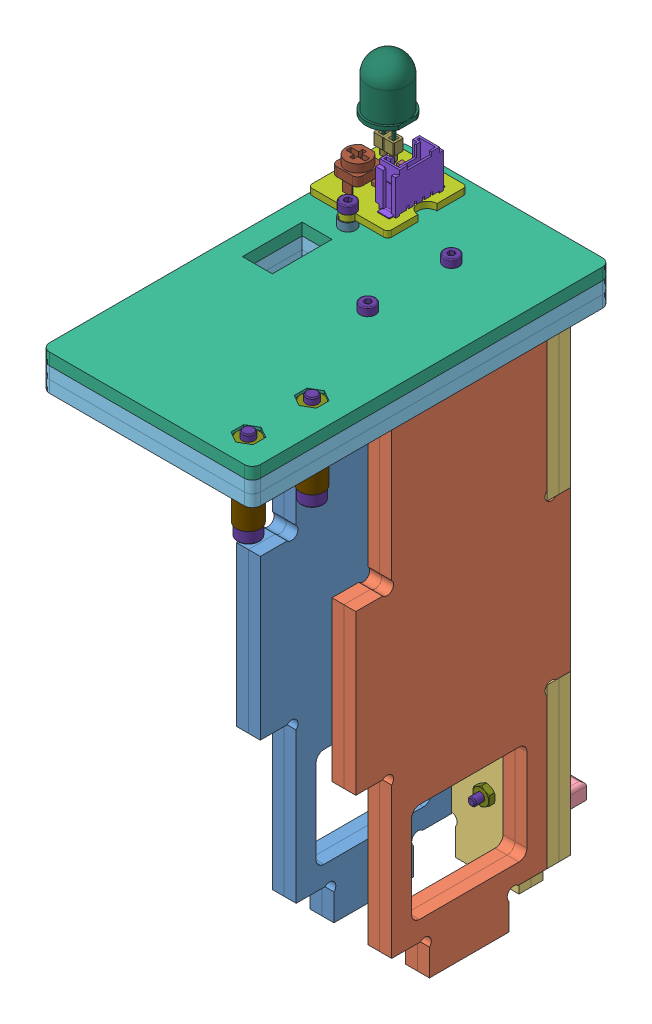
SolidWorks assembly pilier_droit, configuration Défaut. Lengths in mm.
Overall size (53 165.17 99).
42 component instances, 19 part files, 81 mates.
Components (placement in the parent):
- pilier-cote-2-1: pilier-cote-2 [Défaut] at (-45.8322 -68.3923 0) size (3 133 54)
- pilier-cote-3-2: pilier-cote-3 [Défaut] at (-18.8322 -68.3923 0) size (3 133 54)
- pilier-devant-1: pilier-devant [Défaut] at (-45.8322 -68.3923 -54) size (30 133 3)
- pilier-devant-2: pilier-devant [Défaut] at (-45.8322 -68.3923 -51) size (30 133 3)
- pilier-cote-2-3: pilier-cote-2 [Défaut] at (-42.8322 -68.3923 0) size (3 133 54)
- pilier-cote-3-4: pilier-cote-3 [Défaut] at (-21.8322 -68.3923 0) size (3 133 54)
- equerre-1: equerre [Défaut] at (-30.8322 -59.3923 -54) x (-1 0 0) z (0 0 -1) size (10 14 14)
- pilier_droit-chapeau-1-1: pilier_droit-chapeau-1 [Défaut] at (-63.8322 60.6077 31) size (53 3 90)
- pilier_droit-chapeau-1-2: pilier_droit-chapeau-1 [Défaut] at (-63.8322 63.6077 31) size (53 3 90)
- pilier_droit-chapeau-2-1: pilier_droit-chapeau-2 [Défaut] at (-63.8322 66.6077 31) size (53 3 90)
- Grove support LED-1: Grove support LED [Défaut] at (-59.2877 75.7919 -44) size (20 13.2 23.6)
  - PCB grove 20x20-1: PCB grove 20x20 [Défaut] at (7.4555 -4.1841 0) size (20 1.6 23.6)
  - Connecteur Grove (droit CMS)-1: Connecteur Grove (droit CMS) [Défaut] at (10.4555 -2.5841 0) x (-1 0 0) z (0 1 0) size (6.5 14 10)
  - 603 resistor 102-2: 603 resistor 102 [Default] at (3.6365 -2.5841 -1.49) size (2.36 0.62 1.03)
  - 603 cap on pad-1: 603 cap on pad [Défaut] at (8.4655 -2.5841 -6.62) x (0 0 1) z (-1 0 0) size (2.76 0.91 1.12)
  - 603 resistor 102-3: 603 resistor 102 [Default] at (6.6365 -2.5841 -1.49) size (2.36 0.62 1.03)
  - 603 resistor 102-4: 603 resistor 102 [Default] at (6.6365 -2.5841 -2.99) size (2.36 0.62 1.03)
  - Pot - RES_VAR1-1: Pot - RES_VAR1 [Défaut] at (4.0824 2.7159 4.0972) size (6.5 10.5 7.06)
  - Contact F-1: Contact F [Défaut] at (0.621 0.0871 -5.7728) size (2.54 7.5 2.54)
  - ssot3-1: ssot3 [Default] at (6.0932 -2.5841 -5.7439) size (3 1.13 3.09)
  - Contact F-2: Contact F [Défaut] at (3.161 0.0871 -5.7728) size (2.54 7.5 2.54)
- entretoise-grove-1: entretoise-grove [Défaut] at (-51.8322 71.6077 -34) x (1 0 0) z (0 -1 0) size (4 4 2)
- chapeau_pilier_droit-led_jaune-10-1: chapeau_pilier_droit-led_jaune-10 [Default] at (-57.5966 83.2789 -49.8228) x (1 0 0) z (0 1 0) size (10.5 11 23.5)
- entretoise-grove-2: entretoise-grove [Défaut] at (-51.8322 71.6077 -54) x (1 0 0) z (0 -1 0) size (4 4 2)
- ecrou-h-1: ecrou-h [6007 HU M2] at (-51.8322 60.6077 -54) x (0.5 0 0.866025) z (-0.866025 0 0.5) size (4 1.6 4.62)
- vis-chc-1: vis-chc [Vis CHC M2x16] at (-51.8322 73.2077 -54) x (0.657231 0 0.753689) z (-0.753689 0 0.657231) size (3.8 18 3.8)
- vis-chc-2: vis-chc [Vis CHC M2x16] at (-51.8322 73.2077 -34) x (0.657231 0 0.753689) z (-0.753689 0 0.657231) size (3.8 18 3.8)
- ecrou-h-2: ecrou-h [6007 HU M2] at (-51.8322 60.6077 -34) x (-0.866025 0 0.5) z (-0.5 0 -0.866025) size (4 1.6 4.62)
- vis-chc-3: vis-chc [Vis CHC M3x20] at (-18.8322 50.6077 24) x (-0.990761 0 0.135623) z (0.135623 0 0.990761) size (5.5 23 5.5)
- vis-chc-4: vis-chc [Vis CHC M3x20] at (-18.8322 50.6077 8) x (-0.990761 0 0.135623) z (0.135623 0 0.990761) size (5.5 23 5.5)
- ecrou-h-4: ecrou-h [6012 HU M3] at (-18.8322 69.0077 8) x (0.5 0 0.866025) z (-0.866025 0 0.5) size (5.5 2.4 6.35)
- ecrou-h-5: ecrou-h [6012 HU M3] at (-18.8322 69.0077 24) x (-0.5 0 0.866025) z (-0.866025 0 -0.5) size (5.5 2.4 6.35)
- ecrou-h-6: ecrou-h [6007 HU M2] at (-30.8322 51.6077 -46) x (-0.866025 0.5 0) z (-0.5 -0.866025 0) size (4 1.6 4.62)
- ecrou-h-7: ecrou-h [6007 HU M2] at (-30.8322 58.6077 -39) x (0 0 -1) z (1 0 0) size (4 1.6 4.62)
- vis-chc-5: vis-chc [Vis CHC M2x12] at (-30.8322 51.6077 -54) x (0.657231 0.753689 0) z (-0.753689 0.657231 0) size (3.8 14 3.8)
- vis-chc-6: vis-chc [Vis CHC M2x16] at (-30.8322 69.6077 -39) x (-0.137988 0 -0.990434) z (0.990434 0 -0.137988) size (3.8 18 3.8)
- vis-chc-7: vis-chc [Vis CHC M2x16] at (-30.8322 69.6077 -18) x (-0.137988 0 -0.990434) z (0.990434 0 -0.137988) size (3.8 18 3.8)
- grille-patin-1: grille-patin [Défaut] at (-18.8322 60.6077 8) x (0.804119 0 0.594469) z (0 -1 0) size (6 6 10)
- grille-patin-2: grille-patin [Défaut] at (-18.8322 60.6077 24) x (-0.010244 0 0.999948) z (0 -1 0) size (6 6 10)
- equerre-double_ecrou-2: equerre-double_ecrou [Défaut] at (-30.8322 60.6077 -48) x (-1 0 0) z (0 0 1) size (10 14 14)
- vis-chc-8: vis-chc [Vis CHC M2x12] at (-30.8322 -50.3923 -56) x (0.657231 0.753689 0) z (-0.753689 0.657231 0) size (3.8 14 3.8)
- ecrou-h-8: ecrou-h [6007 HU M2] at (-30.8322 -50.3923 -46.4) x (0.5 -0.866025 0) z (-0.866025 -0.5 0) size (4 1.6 4.62)
Mates (geometry in assembly coordinates):
- Coïncidente1: coincident aligned: plane of pilier-cote-2-1 through (-42.8322 60.6077 -40.7627) normal (0 1 0); plane of pilier-devant-1 through (-41.0949 60.6077 -51) normal (0 1 0)
- Coïncidente2: coincident aligned: plane of pilier-cote-2 through (-15.8322 60.6077 -40.7627) normal (0 1 0); plane of pilier-devant-1 through (-20.5694 60.6077 -51) normal (0 1 0)
- Coïncidente3: coincident aligned: plane of pilier-cote-2-1 through (-45.8322 -20.5236 -49.1314) normal (-1 0 0); plane of pilier-devant-1 through (-45.8322 20.6077 -51) normal (-1 0 0)
- Coïncidente4: coincident aligned: plane of pilier-cote-2-1 through (-42.8322 20.6077 -54) normal (0 0 -1); plane of pilier-devant-1 through (-21.7008 -60.5236 -54) normal (0 0 -1)
- Coïncidente5: coincident aligned: plane of pilier-cote-2 through (-15.8322 20.6077 -54) normal (0 0 -1); plane of pilier-devant-1 through (-21.7008 -60.5236 -54) normal (0 0 -1)
- Coïncidente6: coincident aligned: plane of pilier-cote-2 through (-15.8322 -20.5236 -49.1314) normal (1 0 0); plane of pilier-devant-1 through (-15.8322 20.6077 -51) normal (1 0 0)
- Coïncidente7: coincident anti-aligned: plane of pilier-devant-1 through (-21.7008 -60.5236 -51) normal (0 0 1); plane of pilier-devant-2 through (-21.7008 -60.5236 -51) normal (0 0 -1)
- Coïncidente8: coincident aligned: plane of pilier-devant-1 through (-38.8322 64.6077 -51) normal (0 1 0); plane of pilier-devant-2 through (-38.8322 64.6077 -48) normal (0 1 0)
- Coïncidente9: coincident aligned: plane of pilier-devant-1 through (-15.8322 20.6077 -51) normal (1 0 0); plane of pilier-devant-2 through (-15.8322 20.6077 -48) normal (1 0 0)
- Coïncidente11: coincident anti-aligned: plane of pilier-cote-2-1 through (-42.8322 -20.5236 -49.1314) normal (1 0 0); plane of pilier-cote-2-3 through (-42.8322 -20.5236 -49.1314) normal (-1 0 0)
- Coïncidente12: coincident aligned: plane of pilier-cote-2-1 through (-42.8322 64.6077 -18.5) normal (0 1 0); plane of pilier-cote-2-3 through (-39.8322 64.6077 -18.5) normal (0 1 0)
- Coïncidente13: coincident aligned: plane of pilier-cote-2-1 through (-42.8322 20.6077 -54) normal (0 0 -1); plane of pilier-cote-2-3 through (-39.8322 20.6077 -54) normal (0 0 -1)
- Coïncidente14: coincident anti-aligned: plane of pilier-cote-2 through (-18.8322 -20.5236 -49.1314) normal (-1 0 0); plane of pilier-cote-4 through (-18.8322 -20.5236 -49.1314) normal (1 0 0)
- Coïncidente15: coincident aligned: plane of pilier-cote-2 through (-15.8322 64.6077 -18.5) normal (0 1 0); plane of pilier-cote-4 through (-18.8322 64.6077 -18.5) normal (0 1 0)
- Coïncidente16: coincident: line of pilier-cote-2 through (-18.8322 22.8705 -48) axis (0 1 0); plane of pilier-cote-4 through (-18.8322 60.6077 -48) normal (0 0 -1)
- Coïncidente17: coincident anti-aligned: plane of pilier-devant-1 through (-21.7008 -60.5236 -54) normal (0 0 -1); plane of equerre-1 through (-30.8322 -59.3923 -54) normal (0 0 1)
- Coïncidente18: coincident aligned: plane of pilier-devant-1 through (-20.5694 -59.3923 -51) normal (0 -1 0); plane of equerre-1 through (-25.8322 -59.3923 -58) normal (0 -1 0)
- Coaxiale1: concentric anti-aligned: cylinder of pilier-devant-1 through (-30.8322 -50.3923 -54) axis (0 0 1) radius 1; cylinder of equerre-1 through (-30.8322 -50.3923 -54) axis (0 0 -1) radius 1
- Coïncidente19: coincident anti-aligned: plane of pilier-devant-2 through (-21.7008 -60.5236 -48) normal (0 0 1); plane of chapeau_pilier_droit-1 through (-25.0949 63.6077 -48) normal (0 0 -1)
- Coïncidente20: coincident anti-aligned: plane of pilier-devant-1 through (-38.8322 62.8705 -51) normal (-1 0 0); plane of chapeau_pilier_droit-1 through (-38.8322 63.6077 -51.7373) normal (1 0 0)
- Coïncidente21: coincident anti-aligned: plane of pilier-devant-1 through (-41.0949 60.6077 -51) normal (0 1 0); plane of chapeau_pilier_droit-1 through (-12.8322 60.6077 -57) normal (0 -1 0)
- Coïncidente22: coincident anti-aligned: plane of chapeau_pilier_droit-1 through (-12.8322 63.6077 -57) normal (0 1 0); plane of chapeau_pilier_droit-2 through (-12.8322 63.6077 -57) normal (0 -1 0)
- Coïncidente23: coincident aligned: plane of chapeau_pilier_droit-1 through (-63.8322 63.6077 -57) normal (-1 0 0); plane of chapeau_pilier_droit-2 through (-63.8322 66.6077 -57) normal (-1 0 0)
- Coïncidente24: coincident aligned: plane of chapeau_pilier_droit-1 through (-61.8322 63.6077 -59) normal (0 0 -1); plane of chapeau_pilier_droit-2 through (-61.8322 66.6077 -59) normal (0 0 -1)
- Coïncidente25: coincident anti-aligned: plane of chapeau_pilier_droit-2 through (-12.8322 66.6077 -57) normal (0 1 0); plane of pilier_droit-chapeau-2-1 through (-12.8322 66.6077 -57) normal (0 -1 0)
- Coïncidente26: coincident aligned: plane of chapeau_pilier_droit-2 through (-63.8322 66.6077 -57) normal (-1 0 0); plane of pilier_droit-chapeau-2-1 through (-63.8322 69.6077 -57) normal (-1 0 0)
- Coïncidente27: coincident aligned: plane of chapeau_pilier_droit-2 through (-61.8322 66.6077 -59) normal (0 0 -1); plane of pilier_droit-chapeau-2-1 through (-61.8322 69.6077 -59) normal (0 0 -1)
- Coaxiale2: concentric anti-aligned: cylinder of Grove support LED-1/PCB grove 20x20-1 through (-51.8322 73.2077 -34) axis (0 -1 0) radius 1.1; cylinder of entretoise-grove-1 through (-51.8322 69.6077 -34) axis (0 1 0) radius 1
- Distance1: distance = 5 mm: line of Grove support LED-1/Contact F-2 through (-55.8266 78.2789 -50.0728) axis (-1 0 0); line of chapeau_pilier_droit-led_jaune-10-1 through (-56.3266 73.2789 -50.0728) axis (1 0 0)
- Coaxiale3: concentric anti-aligned: cylinder of Grove support LED-1/PCB grove 20x20-1 through (-51.8322 73.2077 -54) axis (0 -1 0) radius 1.1; cylinder of entretoise-grove-2 through (-51.8322 69.6077 -54) axis (0 1 0) radius 1
- Coïncidente28: coincident anti-aligned: plane of Grove support LED-1/PCB grove 20x20-1 through (-51.8322 71.6077 -44) normal (0 -1 0); plane of entretoise-grove-1 through (-51.8322 71.6077 -34) normal (0 1 0)
- Coïncidente29: coincident anti-aligned: plane of Grove support LED-1/Contact F-2 through (-55.8266 78.6789 -49.4728) normal (-1 0 0); plane of chapeau_pilier_droit-led_jaune-10-1 through (-55.8266 83.2789 -50.0728) normal (1 0 0)
- Coïncidente30: coincident anti-aligned: plane of Grove support LED-1/Contact F-2 through (-56.4266 78.6789 -50.0728) normal (0 0 1); plane of chapeau_pilier_droit-led_jaune-10-1 through (-57.5966 83.2789 -50.0728) normal (0 0 -1)
- Coïncidente31: coincident anti-aligned: plane of Grove support LED-1/PCB grove 20x20-1 through (-51.8322 71.6077 -44) normal (0 -1 0); plane of entretoise-grove-2 through (-51.8322 71.6077 -54) normal (0 1 0)
- Coïncidente32: coincident anti-aligned: plane of pilier_droit-chapeau-2-1 through (-12.8322 69.6077 -57) normal (0 1 0); plane of entretoise-grove-2 through (-51.8322 69.6077 -54) normal (0 -1 0)
- Coaxiale4: concentric aligned: cylinder of pilier_droit-chapeau-2-1 through (-51.8322 66.6077 -54) axis (0 1 0) radius 1; cylinder of entretoise-grove-2 through (-51.8322 69.6077 -54) axis (0 1 0) radius 1
- Coaxiale5: concentric anti-aligned: cylinder of pilier_droit-chapeau-2-1 through (-51.8322 66.6077 -34) axis (0 1 0) radius 1; cylinder of Grove support LED-1/PCB grove 20x20-1 through (-51.8322 73.2077 -34) axis (0 -1 0) radius 1.1
- Coaxiale6: concentric anti-aligned: cylinder of Grove support LED-1/PCB grove 20x20-1 through (-51.8322 73.2077 -34) axis (0 -1 0) radius 1.1; cylinder of vis-chc-2 through (-51.8322 57.2077 -34) axis (0 1 0) radius 1
- Coaxiale7: concentric anti-aligned: cylinder of Grove support LED-1/PCB grove 20x20-1 through (-51.8322 73.2077 -54) axis (0 -1 0) radius 1.1; cylinder of vis-chc-1 through (-51.8322 57.2077 -54) axis (0 1 0) radius 1
- Coïncidente33: coincident anti-aligned: plane of Grove support LED-1/PCB grove 20x20-1 through (-51.8322 73.2077 -44) normal (0 1 0); plane of vis-chc-2 through (-51.8322 73.2077 -34) normal (0 -1 0)
- Coïncidente34: coincident anti-aligned: plane of Grove support LED-1/PCB grove 20x20-1 through (-51.8322 73.2077 -44) normal (0 1 0); plane of vis-chc-1 through (-51.8322 73.2077 -54) normal (0 -1 0)
- Coïncidente35: coincident anti-aligned: plane of chapeau_pilier_droit-1 through (-12.8322 60.6077 -57) normal (0 -1 0); plane of ecrou-h-1 through (-49.8322 60.6077 -52.8453) normal (0 1 0)
- Coaxiale8: concentric aligned: cylinder of ecrou-h-1 through (-51.8322 59.0077 -54) axis (0 1 0) radius 0.7835; cylinder of vis-chc-1 through (-51.8322 57.2077 -54) axis (0 1 0) radius 1
- Parallèle1: parallel aligned: plane of chapeau_pilier_droit-1 through (-63.8322 63.6077 -57) normal (-1 0 0); plane of ecrou-h-1 through (-53.8322 59.0077 -55.1547) normal (-1 0 0)
- Coïncidente37: coincident anti-aligned: plane of chapeau_pilier_droit-1 through (-12.8322 60.6077 -57) normal (0 -1 0); plane of ecrou-h-2 through (-52.9869 60.6077 -32) normal (0 1 0)
- Coaxiale9: concentric aligned: cylinder of vis-chc-2 through (-51.8322 57.2077 -34) axis (0 1 0) radius 1; cylinder of ecrou-h-2 through (-51.8322 59.0077 -34) axis (0 1 0) radius 0.7835
- Parallèle2: parallel aligned: plane of chapeau_pilier_droit-1 through (-61.8322 63.6077 -59) normal (0 0 -1); plane of ecrou-h-2 through (-50.6775 59.0077 -36) normal (0 0 -1)
- Coaxiale10: concentric anti-aligned: cylinder of chapeau_pilier_droit-1 through (-18.8322 63.6077 24) axis (0 -1 0) radius 1.5; cylinder of entretoise-6x10-2 through (-18.8322 50.6077 24) axis (0 1 0) radius 2
- Coaxiale11: concentric anti-aligned: cylinder of chapeau_pilier_droit-1 through (-18.8322 63.6077 8) axis (0 -1 0) radius 1.5; cylinder of entretoise-6x10-1 through (-18.8322 50.6077 8) axis (0 1 0) radius 2
- Coïncidente39: coincident anti-aligned: plane of chapeau_pilier_droit-1 through (-12.8322 60.6077 -57) normal (0 -1 0); plane of entretoise-6x10-2 through (-18.8322 60.6077 24) normal (0 1 0)
- Coïncidente40: coincident anti-aligned: plane of chapeau_pilier_droit-1 through (-12.8322 60.6077 -57) normal (0 -1 0); plane of entretoise-6x10-1 through (-18.8322 60.6077 8) normal (0 1 0)
- Coaxiale12: concentric anti-aligned: cylinder of entretoise-6x10-2 through (-18.8322 50.6077 24) axis (0 1 0) radius 2; cylinder of vis-chc-3 through (-18.8322 70.6077 24) axis (0 -1 0) radius 1.5
- Coïncidente41: coincident anti-aligned: plane of entretoise-6x10-2 through (-18.8322 50.6077 24) normal (0 -1 0); plane of vis-chc-3 through (-18.8322 50.6077 24) normal (0 1 0)
- Coaxiale13: concentric anti-aligned: cylinder of entretoise-6x10-1 through (-18.8322 50.6077 8) axis (0 1 0) radius 2; cylinder of vis-chc-4 through (-18.8322 70.6077 8) axis (0 -1 0) radius 1.5
- Coïncidente42: coincident anti-aligned: plane of entretoise-6x10-1 through (-18.8322 50.6077 8) normal (0 -1 0); plane of vis-chc-4 through (-18.8322 50.6077 8) normal (0 1 0)
- Coaxiale14: concentric anti-aligned: cylinder of vis-chc-4 through (-18.8322 70.6077 8) axis (0 -1 0) radius 1.5; cylinder of ecrou-h-4 through (-18.8322 66.6077 8) axis (0 1 0) radius 1.2295
- Parallèle3: parallel anti-aligned: plane of pilier_droit-chapeau-2-1 through (-21.6035 66.6077 6.4971) normal (1 0 0); plane of ecrou-h-4 through (-21.5822 66.6077 6.4123) normal (-1 0 0)
- Coaxiale15: concentric anti-aligned: cylinder of vis-chc-3 through (-18.8322 70.6077 24) axis (0 -1 0) radius 1.5; cylinder of ecrou-h-5 through (-18.8322 66.6077 24) axis (0 1 0) radius 1.2295
- Parallèle4: parallel anti-aligned: plane of pilier_droit-chapeau-2-1 through (-21.6035 66.6077 22.4) normal (1 0 0); plane of ecrou-h-5 through (-21.5822 66.6077 22.4123) normal (-1 0 0)
- Coïncidente45: coincident anti-aligned: plane of chapeau_pilier_droit-2 through (-12.8322 66.6077 -57) normal (0 1 0); plane of ecrou-h-5 through (-18.8322 66.6077 27.1754) normal (0 -1 0)
- Coïncidente46: coincident anti-aligned: plane of chapeau_pilier_droit-2 through (-12.8322 66.6077 -57) normal (0 1 0); plane of ecrou-h-4 through (-16.0822 66.6077 9.5877) normal (0 -1 0)
- Coaxiale16: concentric aligned: cylinder of pilier-devant-2 through (-30.8322 51.6077 -51) axis (0 0 1) radius 1; cylinder of equerre-double_ecrou-2 through (-30.8322 51.6077 -48) axis (0 0 1) radius 1
- Coïncidente47: coincident anti-aligned: plane of pilier-devant-2 through (-21.7008 -60.5236 -48) normal (0 0 1); plane of equerre-double_ecrou-2 through (-30.8322 60.6077 -48) normal (0 0 -1)
- Coïncidente48: coincident anti-aligned: plane of chapeau_pilier_droit-1 through (-12.8322 60.6077 -57) normal (0 -1 0); plane of equerre-double_ecrou-2 through (-25.8322 60.6077 -44) normal (0 1 0)
- Coaxiale17: concentric anti-aligned: cylinder of equerre-double_ecrou-2 through (-30.8322 51.6077 -48) axis (0 0 1) radius 1; cylinder of ecrou-h-6 through (-30.8322 51.6077 -44.4) axis (0 0 -1) radius 0.7835
- Parallèle5: parallel anti-aligned: plane of equerre-double_ecrou-2 through (-29.6672 49.5899 -46) normal (-0.866025 0.5 0); plane of ecrou-h-6 through (-28.5228 51.6077 -44.4) normal (0.866025 -0.5 0)
- Coïncidente51: coincident anti-aligned: plane of equerre-double_ecrou-2 through (-30.8322 60.6077 -46) normal (0 0 1); plane of ecrou-h-6 through (-31.9869 53.6077 -46) normal (0 0 -1)
- Coaxiale18: concentric anti-aligned: cylinder of equerre-double_ecrou-2 through (-30.8322 60.6077 -39) axis (0 -1 0) radius 1; cylinder of ecrou-h-7 through (-30.8322 57.0077 -39) axis (0 1 0) radius 0.7835
- Parallèle6: parallel anti-aligned: plane of equerre-double_ecrou-2 through (-31.9972 58.6077 -41.0178) normal (0 0 1); plane of ecrou-h-7 through (-29.6775 57.0077 -41) normal (0 0 -1)
- Coïncidente53: coincident anti-aligned: plane of equerre-double_ecrou-2 through (-30.8322 58.6077 -48) normal (0 -1 0); plane of ecrou-h-7 through (-31.9869 58.6077 -41) normal (0 1 0)
- Coaxiale19: concentric anti-aligned: cylinder of pilier-devant-1 through (-30.8322 51.6077 -54) axis (0 0 1) radius 1; cylinder of vis-chc-5 through (-30.8322 51.6077 -42) axis (0 0 -1) radius 1
- Coïncidente54: coincident anti-aligned: plane of pilier-devant-1 through (-21.7008 -60.5236 -54) normal (0 0 -1); plane of vis-chc-5 through (-30.8322 51.6077 -54) normal (0 0 1)
- Coaxiale20: concentric aligned: cylinder of pilier_droit-chapeau-2-1 through (-30.8322 66.6077 -39) axis (0 1 0) radius 1; cylinder of vis-chc-6 through (-30.8322 53.6077 -39) axis (0 1 0) radius 1
- Coïncidente55: coincident anti-aligned: plane of pilier_droit-chapeau-2-1 through (-12.8322 69.6077 -57) normal (0 1 0); plane of vis-chc-6 through (-30.8322 69.6077 -39) normal (0 -1 0)
- Coaxiale21: concentric aligned: cylinder of pilier_droit-chapeau-2-1 through (-30.8322 66.6077 -18) axis (0 1 0) radius 1; cylinder of vis-chc-7 through (-30.8322 53.6077 -18) axis (0 1 0) radius 1
- Coïncidente56: coincident anti-aligned: plane of pilier_droit-chapeau-2-1 through (-12.8322 69.6077 -57) normal (0 1 0); plane of vis-chc-7 through (-30.8322 69.6077 -18) normal (0 -1 0)
- Coaxiale22: concentric aligned: cylinder of equerre-1 through (-30.8322 -50.3923 -54) axis (0 0 -1) radius 1; cylinder of vis-chc-8 through (-30.8322 -50.3923 -44) axis (0 0 -1) radius 1
- Coïncidente57: coincident anti-aligned: plane of equerre-1 through (-30.8322 -50.3923 -56) normal (0 0 -1); plane of vis-chc-8 through (-30.8322 -50.3923 -56) normal (0 0 1)
- Coaxiale23: concentric anti-aligned: cylinder of vis-chc-8 through (-30.8322 -50.3923 -44) axis (0 0 -1) radius 1; cylinder of ecrou-h-8 through (-30.8322 -50.3923 -48) axis (0 0 1) radius 0.7835
- Coïncidente58: coincident anti-aligned: plane of pilier-devant-2 through (-21.7008 -60.5236 -48) normal (0 0 1); plane of ecrou-h-8 through (-28.8322 -51.547 -48) normal (0 0 -1)
- Parallèle7: parallel aligned: plane of pilier-devant-2 through (-45.8322 -19.3923 -48) normal (-1 0 0); plane of ecrou-h-8 through (-32.8322 -49.2375 -48) normal (-1 0 0)
